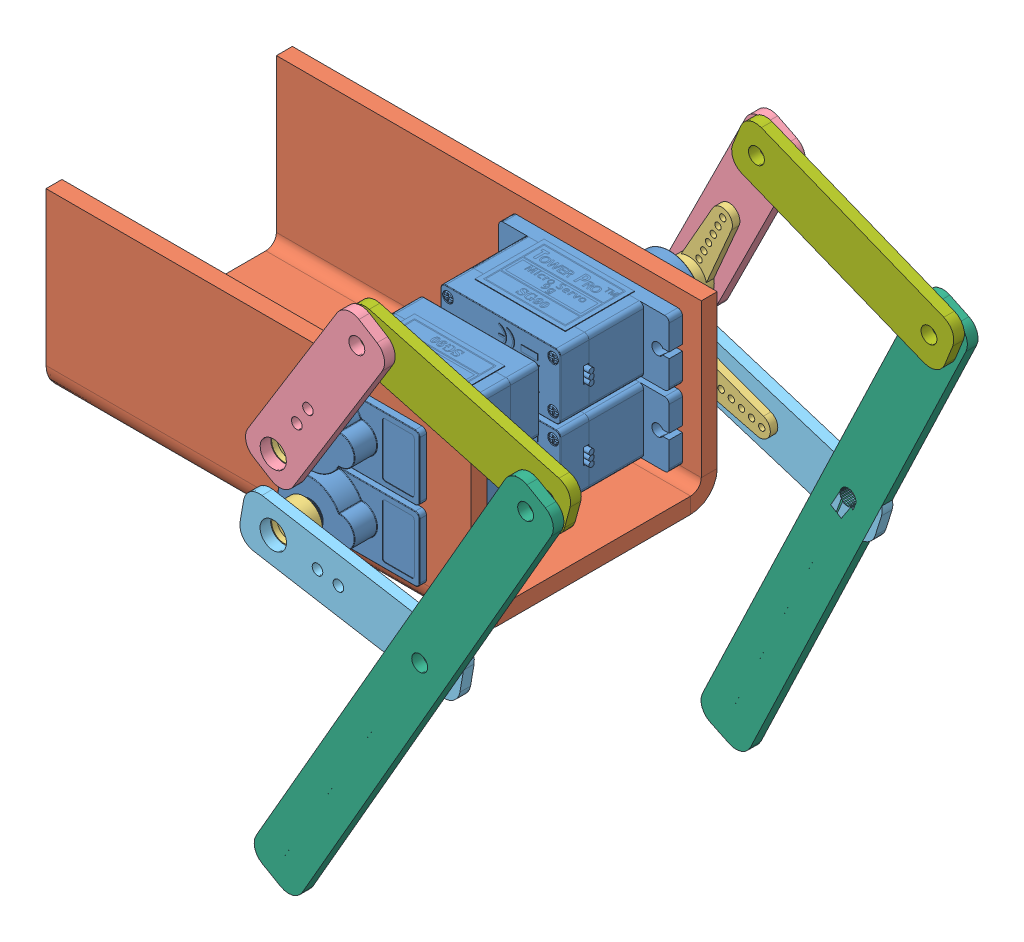
SolidWorks assembly assembly of duck round 3, configuration Default. Lengths in mm.
Overall size (121.36 107.89 73.29).
17 component instances, 7 part files, 43 mates.
Components (placement in the parent):
- SG90 - Micro Servo 9g - Tower Pro.1-1: SG90 - Micro Servo 9g - Tower Pro.1 [Peça] at (70.4693 23.0678 22.9736) x (1 0 0) z (0 -1 0) size (32.1 29.95 12.4)
- SG90 - Micro Servo 9g - Tower Pro.1-2: SG90 - Micro Servo 9g - Tower Pro.1 [Peça] at (70.4693 36.3255 22.9736) x (1 0 0) z (0 -1 0) size (32.1 29.95 12.4)
- frame for duck-1: frame for duck [Default] at (10.0739 -1.8608 10.4263) x (0 0 -1) z (1 0 0) size (46.39 33.84 80)
- SG90 - Micro Servo 9g - Tower Pro.2-1: SG90 - Micro Servo 9g - Tower Pro.2 [Peça] at (65.3193 36.3255 44.0736) x (-0.524612 -0.851341 0) z (-0.851341 0.524612 0) size (19.5 3.8 6.9)
- SG90 - Micro Servo 9g - Tower Pro.2-2: SG90 - Micro Servo 9g - Tower Pro.2 [Peça] at (65.3193 23.0678 44.0736) x (-0.985736 0.168301 0) z (0.168301 0.985736 0) size (19.5 3.8 6.9)
- arm for servo1-1: arm for servo1 [Default] at (73.1885 49.0956 46.0736) x (-0.524612 -0.851341 0) z (0.851341 -0.524612 0) size (38 2 10)
- arm for servo2-1: arm for servo2 [Default] at (80.1054 20.5433 46.0736) x (-0.985736 0.168301 0) z (-0.168301 -0.985736 0) size (42 2 10)
- arm for servo3-1: arm for servo3 [Default] at (91.9 12.8177 46.0736) x (0.498571 0.866849 0) z (0.866849 -0.498571 0) size (100 2 10)
- arm for servo4-1: arm for servo4 [Default] at (97.946 57.2792 44.0736) x (0.965044 -0.262087 0) z (0.262087 0.965044 0) size (47.82 2 10)
- SG90 - Micro Servo 9g - Tower Pro.1-5: SG90 - Micro Servo 9g - Tower Pro.1 [Peça] at (70.4693 23.0678 -2.121) x (-1 0 0) z (0 -1 0) size (32.1 29.95 12.4)
- SG90 - Micro Servo 9g - Tower Pro.1-6: SG90 - Micro Servo 9g - Tower Pro.1 [Peça] at (70.4693 36.3255 -2.121) x (-1 0 0) z (0 -1 0) size (32.1 29.95 12.4)
- SG90 - Micro Servo 9g - Tower Pro.2-3: SG90 - Micro Servo 9g - Tower Pro.2 [Peça] at (75.6193 23.0678 -23.221) x (-0.954174 0.299251 0) z (-0.299251 -0.954174 0) size (19.5 3.8 6.9)
- SG90 - Micro Servo 9g - Tower Pro.2-4: SG90 - Micro Servo 9g - Tower Pro.2 [Peça] at (75.6193 36.3255 -23.221) x (-0.446267 -0.8949 0) z (0.8949 -0.446267 0) size (19.5 3.8 6.9)
- arm for servo1-2: arm for servo1 [Default] at (82.3133 49.749 -23.221) x (-0.446267 -0.8949 0) z (0.8949 -0.446267 0) size (38 2 10)
- arm for servo2-2: arm for servo2 [Default] at (89.9319 18.579 -23.221) x (-0.954174 0.299251 0) z (-0.299251 -0.954174 0) size (42 2 10)
- arm for servo4-2: arm for servo4 [Default] at (105.2559 56.6737 -21.221) x (0.928488 -0.371362 0) z (0.371362 0.928488 0) size (47.82 2 10)
- arm for servo3-2: arm for servo3 [Default] at (101.6556 8.6776 -25.221) x (0.431497 0.902114 0) z (0.902114 -0.431497 0) size (100 2 10)
Mates (geometry in assembly coordinates):
- Concentric1: concentric: cylinder of SG90 - Micro Servo 9g - Tower Pro.1-2 through (84.3693 36.3255 12.4236) axis (0 0 1) radius 1.1; cylinder of frame for duck-1 through (84.3693 36.3255 30.6236) axis (0 0 1) radius 1
- Concentric2: concentric: cylinder of SG90 - Micro Servo 9g - Tower Pro.1-2 through (56.5693 36.3255 12.4236) axis (0 0 1) radius 1.1; cylinder of frame for duck-1 through (56.5693 36.3255 30.6236) axis (0 0 1) radius 1
- Concentric3: concentric: cylinder of SG90 - Micro Servo 9g - Tower Pro.1-1 through (56.5693 23.0678 12.4236) axis (0 0 1) radius 1.1; cylinder of frame for duck-1 through (56.5693 23.0678 30.6236) axis (0 0 1) radius 1
- Concentric4: concentric: cylinder of SG90 - Micro Servo 9g - Tower Pro.1-1 through (84.3693 23.0678 12.4236) axis (0 0 1) radius 1.1; cylinder of frame for duck-1 through (84.3693 23.0678 30.6236) axis (0 0 1) radius 1
- Coincident1: coincident: plane of SG90 - Micro Servo 9g - Tower Pro.1-2 through (55.2693 31.0755 30.6236) normal (0 0 1); plane of frame for duck-1 through (90.0739 11.9025 30.6236) normal (0 0 -1)
- Coincident2: coincident: plane of SG90 - Micro Servo 9g - Tower Pro.1-1 through (55.2693 17.8178 30.6236) normal (0 0 1); plane of frame for duck-1 through (90.0739 11.9025 30.6236) normal (0 0 -1)
- Coincident3: coincident: plane of SG90 - Micro Servo 9g - Tower Pro.1-2 through (65.3193 36.3255 42.2736) normal (0 0 1); plane of SG90 - Micro Servo 9g - Tower Pro.2-1 through (65.3193 36.3255 42.2736) normal (0 0 -1)
- Concentric5: concentric: circle of SG90 - Micro Servo 9g - Tower Pro.1-2; circle of SG90 - Micro Servo 9g - Tower Pro.2-1
- Coincident5: coincident: plane of SG90 - Micro Servo 9g - Tower Pro.1-1 through (65.3193 23.0678 42.2736) normal (0 0 1); plane of SG90 - Micro Servo 9g - Tower Pro.2-2 through (65.3193 23.0678 42.2736) normal (0 0 -1)
- Concentric6: concentric: circle of SG90 - Micro Servo 9g - Tower Pro.1-1; circle of SG90 - Micro Servo 9g - Tower Pro.2-2
- Concentric7: concentric: cylinder of SG90 - Micro Servo 9g - Tower Pro.2-1 through (65.3193 36.3255 44.0736) axis (0 0 1) radius 2.3; cylinder of arm for servo1-1 through (65.3193 36.3255 47.0736) axis (0 0 -1) radius 2.4729
- Coincident6: coincident: plane of SG90 - Micro Servo 9g - Tower Pro.2-1 through (65.3193 36.3255 44.0736) normal (0 0 1); plane of arm for servo1-1 through (73.1885 49.0956 44.0736) normal (0 0 -1)
- Concentric8: concentric: cylinder of arm for servo1-1 through (69.7523 43.5193 47.0736) axis (0 0 -1) radius 1; cylinder of SG90 - Micro Servo 9g - Tower Pro.2-1 through (69.7523 43.5193 44.0736) axis (0 0 1) radius 0.6
- Coincident7: coincident: plane of SG90 - Micro Servo 9g - Tower Pro.2-2 through (65.3193 23.0678 44.0736) normal (0 0 1); plane of arm for servo2-1 through (80.1054 20.5433 44.0736) normal (0 0 -1)
- Concentric9: concentric: cylinder of SG90 - Micro Servo 9g - Tower Pro.2-2 through (65.3193 23.0678 44.0736) axis (0 0 1) radius 2.3; cylinder of arm for servo2-1 through (65.3193 23.0678 44.0736) axis (0 0 -1) radius 2.5
- Concentric10: concentric: cylinder of arm for servo2-1 through (73.6488 21.6456 47.0736) axis (0 0 -1) radius 1; cylinder of SG90 - Micro Servo 9g - Tower Pro.2-2 through (73.6488 21.6456 44.0736) axis (0 0 1) radius 0.6
- Coincident8: coincident: plane of arm for servo2-1 through (80.1054 20.5433 46.0736) normal (0 0 1); plane of arm for servo3-1 through (91.9 12.8177 46.0736) normal (0 0 -1)
- Concentric11: concentric: cylinder of arm for servo2-1 through (94.8914 18.0188 44.0736) axis (0 0 -1) radius 1.5; cylinder of arm for servo3-1 through (94.8914 18.0188 48.0736) axis (0 0 1) radius 1.5
- Coincident9: coincident: plane of arm for servo1-1 through (73.1885 49.0956 44.0736) normal (0 0 -1); plane of arm for servo4-1 through (97.946 57.2792 44.0736) normal (0 0 1)
- Concentric12: concentric: cylinder of arm for servo1-1 through (81.0577 61.8657 44.0736) axis (0 0 -1) radius 1.5; cylinder of arm for servo4-1 through (81.0577 61.8657 44.0736) axis (0 0 1) radius 1.5
- Concentric13: concentric: cylinder of arm for servo3-1 through (114.8342 52.6927 48.0736) axis (0 0 1) radius 1.5; cylinder of arm for servo4-1 through (114.8342 52.6927 44.0736) axis (0 0 1) radius 1.5
- Coincident10: coincident: plane of frame for duck-1 through (90.0739 11.9025 -9.771) normal (0 0 1); plane of SG90 - Micro Servo 9g - Tower Pro.1-5 through (85.6693 17.8178 -9.771) normal (0 0 -1)
- Concentric15: concentric: circle of frame for duck-1; circle of SG90 - Micro Servo 9g - Tower Pro.1-5
- Concentric17: concentric: circle of frame for duck-1; circle of SG90 - Micro Servo 9g - Tower Pro.1-6
- Coincident12: coincident: plane of frame for duck-1 through (90.0739 11.9025 -9.771) normal (0 0 1); plane of SG90 - Micro Servo 9g - Tower Pro.1-6 through (85.6693 31.0755 -9.771) normal (0 0 -1)
- Coincident13: coincident: plane of SG90 - Micro Servo 9g - Tower Pro.1-5 through (75.6193 23.0678 -21.421) normal (0 0 -1); plane of SG90 - Micro Servo 9g - Tower Pro.2-3 through (75.6193 23.0678 -21.421) normal (0 0 1)
- Concentric18: concentric: circle of SG90 - Micro Servo 9g - Tower Pro.1-5; circle of SG90 - Micro Servo 9g - Tower Pro.2-3
- Coincident16: coincident: plane of SG90 - Micro Servo 9g - Tower Pro.1-6 through (75.6193 36.3255 -21.421) normal (0 0 -1); plane of SG90 - Micro Servo 9g - Tower Pro.2-4 through (75.6193 36.3255 -21.421) normal (0 0 1)
- Concentric19: concentric: circle of SG90 - Micro Servo 9g - Tower Pro.1-6; circle of SG90 - Micro Servo 9g - Tower Pro.2-4
- Coincident21: coincident: plane of arm for servo1-2 through (82.3133 49.749 -23.221) normal (0 0 1); plane of arm for servo4-2 through (105.2559 56.6737 -23.221) normal (0 0 -1)
- Coincident22: coincident: circle of arm for servo1-2; cylinder of arm for servo4-2 through (89.0074 63.1725 -21.221) axis (0 0 1) radius 1.5
- Concentric26: concentric: cylinder of arm for servo4-2 through (121.5044 50.1748 -21.221) axis (0 0 1) radius 1.5; cylinder of arm for servo3-2 through (121.5044 50.1748 -23.221) axis (0 0 1) radius 1.5
- Concentric28: concentric: cylinder of arm for servo3-2 through (95.8954 21.3199 -23.221) axis (0 0 1) radius 1.5; cylinder of ? through (95.8954 21.3199 -25.221) axis (0 0 1) radius 1.5
- Coincident24: coincident: plane of arm for servo4-2 through (105.2559 56.6737 -23.221) normal (0 0 -1); plane of arm for servo3-2 through (101.6556 8.6776 -23.221) normal (0 0 1)
- Concentric29: concentric: cylinder of frame for duck-1 through (84.3693 36.3255 -9.771) axis (0 0 -1) radius 1; cylinder of SG90 - Micro Servo 9g - Tower Pro.1-6 through (84.3693 36.3255 8.429) axis (0 0 -1) radius 1.1
- Concentric30: concentric: cylinder of frame for duck-1 through (56.5693 23.0678 -9.771) axis (0 0 -1) radius 1; cylinder of SG90 - Micro Servo 9g - Tower Pro.1-5 through (56.5693 23.0678 8.429) axis (0 0 -1) radius 1.1
- Coincident25: coincident: plane of SG90 - Micro Servo 9g - Tower Pro.2-4 through (75.6193 36.3255 -23.221) normal (0 0 -1); plane of arm for servo1-2 through (82.3133 49.749 -23.221) normal (0 0 1)
- Concentric31: concentric: cylinder of SG90 - Micro Servo 9g - Tower Pro.2-4 through (75.6193 36.3255 -23.221) axis (0 0 -1) radius 2.3; cylinder of arm for servo1-2 through (75.6193 36.3255 -22.221) axis (0 0 -1) radius 2.4729
- Concentric32: concentric: cylinder of SG90 - Micro Servo 9g - Tower Pro.2-4 through (79.3903 43.8874 -23.221) axis (0 0 -1) radius 0.6; cylinder of arm for servo1-2 through (79.3903 43.8874 -22.221) axis (0 0 -1) radius 1
- Concentric33: concentric: cylinder of SG90 - Micro Servo 9g - Tower Pro.2-3 through (75.6193 23.0678 -23.221) axis (0 0 -1) radius 2.3; cylinder of arm for servo2-2 through (75.6193 23.0678 -25.221) axis (0 0 -1) radius 2.5
- Concentric35: concentric: cylinder of SG90 - Micro Servo 9g - Tower Pro.2-3 through (87.4988 19.3421 -23.221) axis (0 0 -1) radius 0.6; cylinder of arm for servo2-2 through (87.4988 19.3421 -22.221) axis (0 0 -1) radius 1
- Coincident26: coincident: plane of SG90 - Micro Servo 9g - Tower Pro.2-3 through (75.6193 23.0678 -23.221) normal (0 0 -1); plane of arm for servo2-2 through (89.9319 18.579 -23.221) normal (0 0 1)
- Coincident27: coincident: cylinder of arm for servo2-2 through (104.2446 14.0903 -25.221) axis (0 0 -1) radius 1.5; circle of arm for servo3-2
